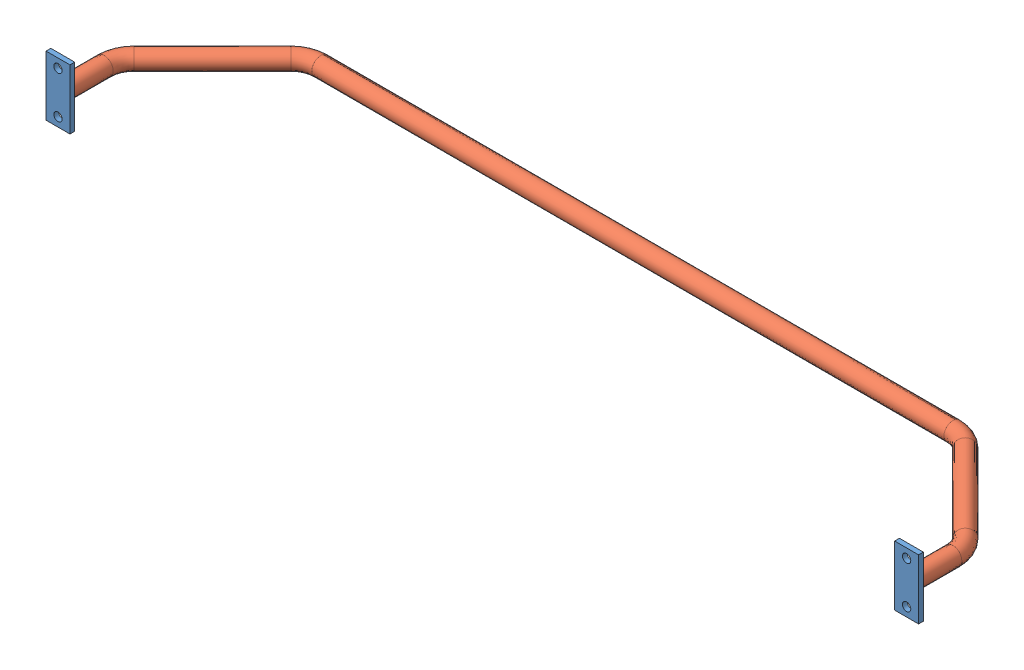
SolidWorks assembly T211-1-00(1), configuration Domyślna. Lengths in mm.
Overall size (1457 100 273).
3 component instances, 2 part files, 7 mates.
Components (placement in the parent):
- płytka pałąka-1: płytka pałąka [Domyślna] at (688.5 -50 0) x (1 0 0) z (0 -1 0) size (40 8 100)
- pałąk ustalający-1: pałąk ustalający [Domyślna] at origin size (1447 30 265)
- płytka pałąka-2: płytka pałąka [Domyślna] at (-728.5 -50 0) x (1 0 0) z (0 -1 0) size (40 8 100)
Mates (geometry in assembly coordinates):
- Wspólnie1: coordinate: point of pałąk ustalający-1; point of assembly
- Wspólnie2: coincident anti-aligned: plane of pałąk ustalający-1 through (-708.5 0 0) normal (0 0 1); plane of płytka pałąka-2 through (-728.5 -50 0) normal (0 0 -1)
- Wspólnie3: coincident aligned: cylinder of pałąk ustalający-1 through (-708.5 0 -69.2893) axis (0 0 1) radius 15; circle of płytka pałąka-2
- Równolegle1: parallel aligned: plane of płytka pałąka-2 through (-688.5 -50 8) normal (1 0 0); plane of assembly through (0 0 0) normal (1 0 0)
- Wspólnie4: coincident anti-aligned: plane of płytka pałąka-1 through (688.5 -50 0) normal (0 0 -1); plane of pałąk ustalający-1 through (708.5 0 0) normal (0 0 1)
- Wspólnie5: coincident aligned: circle of płytka pałąka-1; cylinder of pałąk ustalający-1 through (708.5 0 -69.2893) axis (0 0 1) radius 15
- Równolegle2: parallel anti-aligned: plane of płytka pałąka-1 through (688.5 -50 8) normal (-1 0 0); plane of assembly through (0 0 0) normal (1 0 0)
